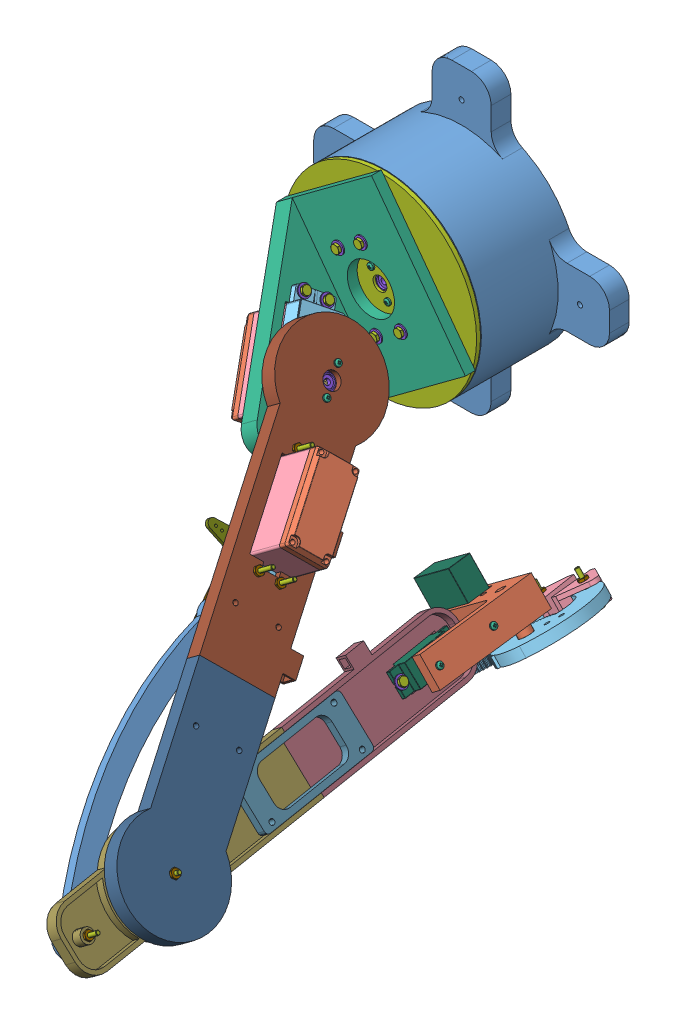
SolidWorks assembly Złożenie1, configuration Domyślna. Lengths in mm.
Overall size (203.19 257.03 301.36).
124 component instances, 27 part files, 135 mates.
Components (placement in the parent):
- Pokrywa-1: Pokrywa [Domyślna] at (39.7266 -62.268 12.8126) size (150 150 49)
- MG_996R-1: MG_996R [Domyślna] at (52.4205 -93.0413 -7.8923) x (-1 0 0) z (0 -1 0) size (19.93 44.4 54.6)
  - Base-1: Base [Domyślna] at (12.6939 -23.8049 -20.4733) size (19.93 6.4 40.73)
  - Eje-1: Eje [Domyślna] at (12.6939 -50.7049 -30.7733) x (-0.837169 0 -0.546944) z (-0.546944 0 0.837169) size (5.78 17.5 5.8)
  - Medio-1: Medio [Domyślna] at (12.6939 -30.2049 -20.4733) size (19.8 20.5 40.6)
  - Top-1: Top [Domyślna] at (12.6939 -59.7049 -20.4733) x (-1 0 0) z (0 0 1) size (19.8 13.2 54.6)
- Złożenie8-1: Złożenie8 [Domyślna] at (-3.3263 -2.2517 0) x (0.998521 0.054362 0) z (0 0 1) size (94.14 109.68 62.96)
  - Mocowanie-1: Mocowanie [Domyślna] at (40.1439 -61.9925 64.2126) x (-0.550863 0.834596 0) z (0 0 1) size (80 60 62.96)
  - MG_996R-1: MG_996R [Domyślna] at (-24.4927 -92.4165 92.8752) x (0.362745 -0.549585 -0.752577) z (-0.414566 0.628098 -0.658505) size (19.93 44.4 54.6)
    - Base-1: Base [Domyślna] at (12.6939 -23.8049 -20.4733) size (19.93 6.4 40.73)
    - Eje-1: Eje [Domyślna] at (12.6939 -50.7049 -30.7733) x (-0.837169 0 -0.546944) z (-0.546944 0 0.837169) size (5.78 17.5 5.8)
    - Medio-1: Medio [Domyślna] at (12.6939 -30.2049 -20.4733) size (19.8 20.5 40.6)
    - Top-1: Top [Domyślna] at (12.6939 -59.7049 -20.4733) x (-1 0 0) z (0 0 1) size (19.8 13.2 54.6)
- Dekiel-3: Dekiel [Domyślna] at (39.7266 -62.268 64.2126) x (-0.595419 0.803416 0) z (0 0 -1) size (98 98 2)
- Orczyk-1: Orczyk [Domyślna] at (39.7266 -62.268 62.2126) x (0.595419 -0.803416 0) z (0.803416 0.595419 0) size (21.5 5.9 21.5)
- Orczyk-2: Orczyk [Domyślna] at (52.3311 -79.4435 103.5865) x (0.375837 -0.507128 0.775608) z (0.461812 -0.623136 -0.631215) size (21.5 5.9 21.5)
- Złożenie3-2: Złożenie3 [Domyślna] at (8.1962 -17.7993 -14.8981) x (0.993577 0.061034 0.095284) z (-0.102991 0.138969 0.984927) size (128.8 189.44 201.48)
  - MG_996R-1: MG_996R [Domyślna] at (112.7095 -80.9773 116.6892) x (-0.360669 0.546439 0.755859) z (-0.416374 0.630837 -0.654735) size (19.93 44.4 54.6)
    - Base-1: Base [Domyślna] at (12.6939 -23.8049 -20.4733) size (19.93 6.4 40.73)
    - Eje-1: Eje [Domyślna] at (12.6939 -50.7049 -30.7733) x (-0.837169 0 -0.546944) z (-0.546944 0 0.837169) size (5.78 17.5 5.8)
    - Medio-1: Medio [Domyślna] at (12.6939 -30.2049 -20.4733) size (19.8 20.5 40.6)
    - Top-1: Top [Domyślna] at (12.6939 -59.7049 -20.4733) x (-1 0 0) z (0 0 1) size (19.8 13.2 54.6)
  - plytka-1: plytka [Domyślna] at (97.1707 -158.5581 182.1546) x (-0.360669 0.546439 0.755859) z (0.834596 0.550863 0) size (28.8 60 5)
  - ramie1-1: ramie1 [Domyślna] at (47.2058 -82.8576 103.5865) x (0.416374 -0.630837 0.654735) z (0.834596 0.550863 0) size (232.1 50 8)
  - ramie-1: ramie [Domyślna] at (47.2058 -82.8576 103.5865) x (0.416374 -0.630837 0.654735) z (0.834596 0.550863 0) size (145 50 8)
- Złożenie4-2: Złożenie4 [Domyślna] at (8.1595 -17.7498 -14.8525) x (0.99359 0.061016 0.095162) z (-0.102859 0.13879 0.984966) size (69.67 92.42 221.23)
  - ramie2-1: ramie2 [Domyślna] at (123.8039 -213.4319 234.5334) x (-0.163325 0.247449 -0.955036) z (0.834596 0.550863 0) size (130 45 13)
  - ramie21-1: ramie21 [Domyślna] at (123.8039 -213.4319 234.5334) x (-0.163325 0.247449 -0.955036) z (0.834596 0.550863 0) size (90 36 6)
  - plytka2-1: plytka2 [Domyślna] at (115.7455 -190.3308 158.1305) x (-0.526093 0.797069 0.29649) z (-0.834596 -0.550863 0) size (25.8 60 4)
  - servo TOWER PRO 9g SG90-1: servo TOWER PRO 9g SG90 [Défaut] at (85.975 -182.4408 103.4882) x (0.163325 -0.247449 0.955036) z (0.834596 0.550863 0) size (32 11.7 29.7)
- 4 Arm-1: 4 Arm [Domyślna] at (57.5904 -115.931 159.4951) x (-0.514712 0.694515 0.502713) z (-0.803416 -0.595419 0) size (39 39 5.5)
- msh-1: msh [По умолчанию] at (119.932 -161.9259 104.7162) x (-0.054685 0.073788 -0.995773) z (-0.803416 -0.595419 0) size (32 7.5 5)
- 111-1: 111 [Domyślna] at (59.2016 -129.4417 159.421) x (-0.299325 0.403888 -0.864453) z (0.803416 0.595419 0) size (54 8 5)
- łacznik-6: łacznik [Domyślna] at (75.4238 -132.4366 180.1679) x (0.318973 -0.430399 0.844401) z (0.502772 -0.678405 -0.535712) size (155 5 25.15)
- podstawa-2: podstawa [Domyślna] at (125.8131 -165.6628 93.5718) x (0.054685 -0.073788 0.995773) z (-0.592902 0.80002 0.091843) size (60 50 19)
- servo TOWER PRO 9g SG90-3: servo TOWER PRO 9g SG90 [Défaut] at (91.2204 -151.7359 70.1421) x (0.803416 0.595419 0) z (0.592902 -0.80002 -0.091843) size (32 11.7 29.7)
- msh1-1: msh1 [По умолчанию] at (98.4601 -188.7964 72.7727) x (-0.566783 -0.333567 -0.753319) z (-0.592902 0.80002 0.091843) size (19.75 7.5 5)
- Złożenie6-3: Złożenie6 [Domyślna] at (10.171 -11.3916 -10.0611) x (0.989879 0.051709 0.132161) z (-0.136721 0.097784 0.985772) size (46 32 64.72)
  - Chwyt-1: Chwyt [Domyślna] at (88.6962 -174.049 17.2042) x (0.795979 0.579475 -0.175003) z (0.533395 -0.808131 -0.249828) size (17.08 20 10)
  - koło_zębate-1: koło_zębate [ISO - Spur gear 1M 30T 20PA 6FW ---S30A75H50L5.0N] at (91.8364 -192.3197 50.9877) x (-0.533395 0.808131 0.249828) z (-0.795979 -0.579475 0.175003) size (5 55.03 34.65)
- Złożenie7-3: Złożenie7 [Domyślna] at (19.6552 -4.3213 -10.4227) x (0.973641 0.028873 0.226252) z (-0.227135 0.032206 0.973331) size (44.29 32.31 61.31)
  - Chwyt-1: Chwyt [Domyślna] at (93.516 -171.6593 20.5651) x (-0.818033 -0.567973 0.090709) z (0.533395 -0.808131 -0.249828) size (17.08 20 10)
  - koło_zębate-1: koło_zębate [ISO - Spur gear 1M 30T 20PA 6FW ---S30A75H50L5.0N] at (114.1006 -171.5915 52.2868) x (0.533395 -0.808131 -0.249828) z (0.818033 0.567973 -0.090709) size (5 55.03 34.65)
- pan head cross recess screw_din-1: pan head cross recess screw_din [DIN EN ISO 7045 - M1.6 x 8 - Z - 8N] at (58.4543 -80.4838 109.0933) x (-0.803416 -0.595419 0) z (0 0 1) size (9.27 3.2 3.2)
- pan head cross recess screw_din-4: pan head cross recess screw_din [DIN EN ISO 7045 - M1.6 x 8 - Z - 8N] at (53.1174 -73.2826 98.0797) x (-0.803416 -0.595419 0) z (0 0 -1) size (9.27 3.2 3.2)
- pan head cross recess screw_din-5: pan head cross recess screw_din [DIN EN ISO 7045 - M1.6 x 8 - Z - 8N] at (35.4992 -56.5637 65.5126) x (0 0 -1) z (1 0 0) size (9.27 3.2 3.2)
- pan head cross recess screw_din-6: pan head cross recess screw_din [DIN EN ISO 7045 - M1.6 x 8 - Z - 8N] at (43.9541 -67.9722 65.5126) x (0 0 -1) z (-1 0 0) size (9.27 3.2 3.2)
- pan head cross recess screw_din-7: pan head cross recess screw_din [DIN EN ISO 7045 - M1.6 x 8 - Z - 8N] at (124.2006 -157.1049 90.2775) x (-0.803416 -0.595419 0) z (0 0 1) size (9.27 3.2 3.2)
- pan head cross recess screw_din-8: pan head cross recess screw_din [DIN EN ISO 7045 - M1.6 x 8 - Z - 8N] at (125.7864 -159.2447 119.1549) x (-0.803416 -0.595419 0) z (0 0 1) size (9.27 3.2 3.2)
- pan head cross recess screw_din-9: pan head cross recess screw_din [DIN EN ISO 7045 - M1.6 x 8 - Z - 8N] at (93.977 -198.6733 61.2709) x (-0.592902 0.80002 0.091843) z (0.742225 0.498675 0.447688) size (9.27 3.2 3.2)
- hex screw gradeab_din-1: hex screw gradeab_din [DIN EN 24017 - M2 x 20-N] at (44.7266 -97.458 47.6126) x (0 0 -1) z (0.923728 0.383049 0) size (21.4 4.62 4)
- plain washer 6902 type abc_din-1: plain washer 6902 type abc_din [DIN 6902-A2.25] at (44.7266 -97.458 45.6126) x (0 0 1) z (0 -1 0) size (0.6 6 6)
- hex thin nut chamfered gradeab_din-2: hex thin nut chamfered gradeab_din [Hexagon Thin Nut ISO 4035 - M2 - N] at (44.7266 -97.458 31.5126) x (0.866025 0.5 0) z (0 0 -1) size (4 4.62 1.2)
- hex thin nut chamfered gradeab_din-3: hex thin nut chamfered gradeab_din [Hexagon Thin Nut ISO 4035 - M2 - N] at (44.7266 -47.958 31.5126) x (0.866025 0.5 0) z (0 0 -1) size (4 4.62 1.2)
- plain washer 6902 type abc_din-3: plain washer 6902 type abc_din [DIN 6902-A2.25] at (44.7266 -47.958 45.6126) x (0 0 1) z (0 -1 0) size (0.6 6 6)
- hex screw gradeab_din-2: hex screw gradeab_din [DIN EN 24017 - M2 x 16-N] at (44.7266 -47.958 47.6126) x (0 0 -1) z (0.923728 0.383049 0) size (17.4 4.62 4)
- hex screw gradeab_din-3: hex screw gradeab_din [DIN EN 24017 - M2 x 20-N] at (34.7266 -97.458 47.6126) x (0 0 -1) z (0.923728 0.383049 0) size (21.4 4.62 4)
- hex screw gradeab_din-4: hex screw gradeab_din [DIN EN 24017 - M2 x 16-N] at (34.7266 -47.958 47.6126) x (0 0 -1) z (0.923728 0.383049 0) size (17.4 4.62 4)
- plain washer 6902 type abc_din-4: plain washer 6902 type abc_din [DIN 6902-A2.25] at (34.7266 -97.458 45.6126) x (0 0 1) z (0 -1 0) size (0.6 6 6)
- plain washer 6902 type abc_din-5: plain washer 6902 type abc_din [DIN 6902-A2.25] at (34.7266 -47.958 45.6126) x (0 0 1) z (0 -1 0) size (0.6 6 6)
- hex thin nut chamfered gradeab_din-4: hex thin nut chamfered gradeab_din [Hexagon Thin Nut ISO 4035 - M2 - N] at (34.7266 -97.458 31.5126) x (0.866025 0.5 0) z (0 0 -1) size (4 4.62 1.2)
- hex thin nut chamfered gradeab_din-5: hex thin nut chamfered gradeab_din [Hexagon Thin Nut ISO 4035 - M2 - N] at (34.7266 -47.958 31.5126) x (0.866025 0.5 0) z (0 0 -1) size (4 4.62 1.2)
- hex screw gradeab_din-5: hex screw gradeab_din [DIN EN 24017 - M2 x 16-N] at (35.3324 -43.7425 71.2126) x (0 0 -1) z (0.923728 0.383049 0) size (17.4 4.62 4)
- plain washer 6902 type abc_din-6: plain washer 6902 type abc_din [DIN 6902-A2.25] at (35.3324 -43.7425 69.2126) x (0 0 1) z (0 -1 0) size (0.6 6 6)
- hex thin nut chamfered gradeab_din-6: hex thin nut chamfered gradeab_din [Hexagon Thin Nut ISO 4035 - M2 - N] at (35.3324 -43.7425 61.0126) x (0.866025 0.5 0) z (0 0 -1) size (4 4.62 1.2)
- hex screw gradeab_din-27: hex screw gradeab_din [DIN EN 24017 - M2 x 16-N] at (55.6262 -72.7419 71.2126) x (0 0 -1) z (0.923728 0.383049 0) size (17.4 4.62 4)
- hex screw gradeab_din-7: hex screw gradeab_din [DIN EN 24017 - M2 x 16-N] at (23.8271 -51.794 71.2126) x (0 0 -1) z (0.923728 0.383049 0) size (17.4 4.62 4)
- hex screw gradeab_din-8: hex screw gradeab_din [DIN EN 24017 - M2 x 16-N] at (43.1073 -81.0049 71.2126) x (0 0 -1) z (0.923728 0.383049 0) size (17.4 4.62 4)
- plain washer 6902 type abc_din-7: plain washer 6902 type abc_din [DIN 6902-A2.25] at (55.6262 -72.7419 69.2126) x (0 0 1) z (0 -1 0) size (0.6 6 6)
- plain washer 6902 type abc_din-8: plain washer 6902 type abc_din [DIN 6902-A2.25] at (23.8271 -51.794 69.2126) x (0 0 1) z (0 -1 0) size (0.6 6 6)
- plain washer 6902 type abc_din-9: plain washer 6902 type abc_din [DIN 6902-A2.25] at (43.1073 -81.0049 69.2126) x (0 0 1) z (0 -1 0) size (0.6 6 6)
- hex thin nut chamfered gradeab_din-7: hex thin nut chamfered gradeab_din [Hexagon Thin Nut ISO 4035 - M2 - N] at (55.6262 -72.7419 61.0126) x (0.866025 0.5 0) z (0 0 -1) size (4 4.62 1.2)
- hex thin nut chamfered gradeab_din-8: hex thin nut chamfered gradeab_din [Hexagon Thin Nut ISO 4035 - M2 - N] at (23.8271 -51.794 61.0126) x (0.866025 0.5 0) z (0 0 -1) size (4 4.62 1.2)
- hex thin nut chamfered gradeab_din-9: hex thin nut chamfered gradeab_din [Hexagon Thin Nut ISO 4035 - M2 - N] at (43.1073 -81.0049 61.0126) x (0.866025 0.5 0) z (0 0 -1) size (4 4.62 1.2)
- hex screw gradeab_din-9: hex screw gradeab_din [DIN EN 24017 - M2 x 16-N] at (26.7931 -69.5049 76.6508) x (-0.803416 -0.595419 0) z (-0.592276 0.799175 0.102607) size (17.4 4.62 4)
- plain washer 6902 type abc_din-10: plain washer 6902 type abc_din [DIN 6902-A2.25] at (25.1863 -70.6957 76.6508) x (0.803416 0.595419 0) z (0.481407 -0.649576 0.588471) size (0.6 6 6)
- hex thin nut chamfered gradeab_din-10: hex thin nut chamfered gradeab_din [Hexagon Thin Nut ISO 4035 - M2 - N] at (13.9385 -79.0316 76.6508) x (-0.327149 0.441431 0.835531) z (-0.803416 -0.595419 0) size (4 4.62 1.2)
- hex screw gradeab_din-10: hex screw gradeab_din [DIN EN 24017 - M2 x 16-N] at (111.5865 -171.155 123.8102) x (-0.803416 -0.595419 0) z (0.140412 -0.189462 -0.971797) size (17.4 4.62 4)
- plain washer 6902 type abc_din-11: plain washer 6902 type abc_din [DIN 6902-A2.25] at (109.9797 -172.3458 123.8102) x (0.803416 0.595419 0) z (0.480708 -0.648634 0.59008) size (0.6 6 6)
- hex thin nut chamfered gradeab_din-11: hex thin nut chamfered gradeab_din [Hexagon Thin Nut ISO 4035 - M2 - N] at (105.8019 -175.442 123.8102) x (0.063919 -0.086248 -0.994221) z (-0.803416 -0.595419 0) size (4 4.62 1.2)
- hex screw gradeab_din-11: hex screw gradeab_din [DIN EN 24017 - M2 x 20-N] at (115.4473 -189.8003 258.7081) x (0.803416 0.595419 0) z (0.083424 -0.112566 -0.990136) size (21.4 4.62 4)
- plain washer 6902 type abc_din-12: plain washer 6902 type abc_din [DIN 6902-A2.25] at (117.0541 -188.6095 258.7081) x (-0.803416 -0.595419 0) z (-0.576535 0.777935 0.249848) size (0.6 6 6)
- hex thin nut chamfered gradeab_din-12: hex thin nut chamfered gradeab_din [Hexagon Thin Nut ISO 4035 - M2 - N] at (130.8729 -178.3683 258.7081) x (0.159434 -0.215129 -0.963483) z (0.803416 0.595419 0) size (4 4.62 1.2)
- hex screw gradeab_din-12: hex screw gradeab_din [DIN EN 24017 - M2 x 16-N] at (57.5347 -94.5265 130.2047) x (0.803416 0.595419 0) z (-0.295441 0.398648 0.868213) size (17.4 4.62 4)
- plain washer 6902 type abc_din-13: plain washer 6902 type abc_din [DIN 6902-A2.25] at (59.1416 -93.3356 130.2047) x (-0.803416 -0.595419 0) z (0.59069 -0.797035 0.125777) size (0.6 6 6)
- hex thin nut chamfered gradeab_din-13: hex thin nut chamfered gradeab_din [Hexagon Thin Nut ISO 4035 - M2 - N] at (64.7655 -89.1677 130.2047) x (-0.360202 0.486031 0.796259) z (0.803416 0.595419 0) size (4 4.62 1.2)
- hex screw gradeab_din-13: hex screw gradeab_din [DIN EN 24017 - M2 x 16-N] at (117.0672 -194.9253 298.384) x (0.803416 0.595419 0) z (-0.02438 0.032896 0.999161) size (17.4 4.62 4)
- plain washer 6902 type abc_din-14: plain washer 6902 type abc_din [DIN 6902-A2.25] at (118.4732 -193.8833 298.384) x (-0.803416 -0.595419 0) z (0.576535 -0.777935 -0.249848) size (0.6 6 6)
- hex thin nut chamfered gradeab_din-14: hex thin nut chamfered gradeab_din [Hexagon Thin Nut ISO 4035 - M2 - N] at (126.668 -187.81 298.384) x (0.159434 -0.215129 -0.963483) z (0.803416 0.595419 0) size (4 4.62 1.2)
- hex screw gradeab_din-14: hex screw gradeab_din [DIN EN 24017 - M2 x 16-N] at (109.4684 -168.2969 96.0371) x (-0.803416 -0.595419 0) z (0.140412 -0.189462 -0.971797) size (17.4 4.62 4)
- plain washer 6902 type abc_din-15: plain washer 6902 type abc_din [DIN 6902-A2.25] at (107.8616 -169.4877 96.0371) x (0.803416 0.595419 0) z (0.480708 -0.648634 0.59008) size (0.6 6 6)
- hex thin nut chamfered gradeab_din-15: hex thin nut chamfered gradeab_din [Hexagon Thin Nut ISO 4035 - M2 - N] at (103.6838 -172.5839 96.0371) x (0.063919 -0.086248 -0.994221) z (-0.803416 -0.595419 0) size (4 4.62 1.2)
- hex screw gradeab_din-15: hex screw gradeab_din [DIN EN 24017 - M2 x 20-N] at (126.5943 -176.374 72.1481) x (-0.592902 0.80002 0.091843) z (0.57607 0.341684 0.74256) size (21.4 4.62 4)
- plain washer 6902 type abc_din-16: plain washer 6902 type abc_din [DIN 6902-A2.25] at (125.4085 -174.7739 72.3318) x (0.592902 -0.80002 -0.091843) z (0.299102 0.324677 -0.897287) size (0.6 6 6)
- hex thin nut chamfered gradeab_din-16: hex thin nut chamfered gradeab_din [Hexagon Thin Nut ISO 4035 - M2 - N] at (116.3964 -162.6136 73.7278) x (0.497947 0.2746 0.822583) z (-0.592902 0.80002 0.091843) size (4 4.62 1.2)
- hex screw gradeab_din-16: hex screw gradeab_din [DIN EN 24017 - M2 x 16-N] at (123.9705 -176.7645 36.8358) x (-0.592902 0.80002 0.091843) z (0.577534 0.342968 0.740829) size (17.4 4.62 4)
- plain washer 6902 type abc_din-17: plain washer 6902 type abc_din [DIN 6902-A2.25] at (122.7847 -175.1645 37.0195) x (0.592902 -0.80002 -0.091843) z (0.297153 0.323361 -0.898408) size (0.6 6 6)
- hex thin nut chamfered gradeab_din-17: hex thin nut chamfered gradeab_din [Hexagon Thin Nut ISO 4035 - M2 - N] at (116.1442 -166.2043 38.0481) x (0.497947 0.2746 0.822583) z (-0.592902 0.80002 0.091843) size (4 4.62 1.2)
- hex screw gradeab_din-17: hex screw gradeab_din [DIN EN 24017 - M2 x 16-N] at (102.2465 -193.1038 36.7434) x (-0.592902 0.80002 0.091843) z (0.770886 0.530906 0.351957) size (17.4 4.62 4)
- plain washer 6902 type abc_din-18: plain washer 6902 type abc_din [DIN 6902-A2.25] at (101.0607 -191.5038 36.9271) x (0.592902 -0.80002 -0.091843) z (0.299102 0.324677 -0.897287) size (0.6 6 6)
- hex thin nut chamfered gradeab_din-18: hex thin nut chamfered gradeab_din [Hexagon Thin Nut ISO 4035 - M2 - N] at (94.4202 -182.5436 37.9557) x (0.497947 0.2746 0.822583) z (-0.592902 0.80002 0.091843) size (4 4.62 1.2)
- hex thin nut chamfered gradeab_din-19: hex thin nut chamfered gradeab_din [Hexagon Thin Nut ISO 4035 - M2 - N] at (33.7024 -108.8716 109.4312) x (-0.302668 0.458563 0.835531) z (-0.834596 -0.550863 0) size (4 4.62 1.2)
- hex thin nut chamfered gradeab_din-20: hex thin nut chamfered gradeab_din [Hexagon Thin Nut ISO 4035 - M2 - N] at (9.5539 -72.2849 84.361) x (-0.302668 0.458563 0.835531) z (-0.834596 -0.550863 0) size (4 4.62 1.2)
- hex thin nut chamfered gradeab_din-21: hex thin nut chamfered gradeab_din [Hexagon Thin Nut ISO 4035 - M2 - N] at (30.0749 -103.3757 116.957) x (-0.302668 0.458563 0.835531) z (-0.834596 -0.550863 0) size (4 4.62 1.2)
- plain washer 6902 type abc_din-19: plain washer 6902 type abc_din [DIN 6902-A2.25] at (45.3867 -101.1595 109.4312) x (0.834596 0.550863 0) z (0.445383 -0.674786 0.588471) size (0.6 6 6)
- plain washer 6902 type abc_din-20: plain washer 6902 type abc_din [DIN 6902-A2.25] at (21.2383 -64.5728 84.361) x (0.834596 0.550863 0) z (0.445383 -0.674786 0.588471) size (0.6 6 6)
- plain washer 6902 type abc_din-21: plain washer 6902 type abc_din [DIN 6902-A2.25] at (41.7593 -95.6637 116.957) x (0.834596 0.550863 0) z (0.445383 -0.674786 0.588471) size (0.6 6 6)
- hex screw gradeab_din-25: hex screw gradeab_din [DIN EN 24017 - M2 x 16-N] at (47.0559 -100.0578 109.4312) x (-0.834596 -0.550863 0) z (-0.547955 0.830191 0.102607) size (17.4 4.62 4)
- hex screw gradeab_din-19: hex screw gradeab_din [DIN EN 24017 - M2 x 16-N] at (22.9074 -63.4711 84.361) x (-0.834596 -0.550863 0) z (-0.547955 0.830191 0.102607) size (17.4 4.62 4)
- hex screw gradeab_din-20: hex screw gradeab_din [DIN EN 24017 - M2 x 16-N] at (43.4285 -94.5619 116.957) x (-0.834596 -0.550863 0) z (-0.547955 0.830191 0.102607) size (17.4 4.62 4)
- hex thin nut chamfered gradeab_din-22: hex thin nut chamfered gradeab_din [Hexagon Thin Nut ISO 4035 - M2 - N] at (83.3694 -114.2705 168.5973) x (-0.360202 0.486031 0.796259) z (0.803416 0.595419 0) size (4 4.62 1.2)
- hex thin nut chamfered gradeab_din-23: hex thin nut chamfered gradeab_din [Hexagon Thin Nut ISO 4035 - M2 - N] at (69.3836 -95.399 123.8926) x (-0.360202 0.486031 0.796259) z (0.803416 0.595419 0) size (4 4.62 1.2)
- hex thin nut chamfered gradeab_din-24: hex thin nut chamfered gradeab_din [Hexagon Thin Nut ISO 4035 - M2 - N] at (87.9875 -120.5019 162.2852) x (-0.360202 0.486031 0.796259) z (0.803416 0.595419 0) size (4 4.62 1.2)
- plain washer 6902 type abc_din-22: plain washer 6902 type abc_din [DIN 6902-A2.25] at (77.7455 -118.4384 168.5973) x (-0.803416 -0.595419 0) z (0.59069 -0.797035 0.125777) size (0.6 6 6)
- plain washer 6902 type abc_din-23: plain washer 6902 type abc_din [DIN 6902-A2.25] at (63.7597 -99.567 123.8926) x (-0.803416 -0.595419 0) z (0.59069 -0.797035 0.125777) size (0.6 6 6)
- plain washer 6902 type abc_din-24: plain washer 6902 type abc_din [DIN 6902-A2.25] at (82.3636 -124.6698 162.2852) x (-0.803416 -0.595419 0) z (0.59069 -0.797035 0.125777) size (0.6 6 6)
- hex screw gradeab_din-26: hex screw gradeab_din [DIN EN 24017 - M2 x 16-N] at (76.1387 -119.6293 168.5973) x (0.803416 0.595419 0) z (-0.295441 0.398648 0.868213) size (17.4 4.62 4)
- hex screw gradeab_din-22: hex screw gradeab_din [DIN EN 24017 - M2 x 16-N] at (62.1529 -100.7578 123.8926) x (0.803416 0.595419 0) z (-0.295441 0.398648 0.868213) size (17.4 4.62 4)
- hex screw gradeab_din-23: hex screw gradeab_din [DIN EN 24017 - M2 x 16-N] at (80.7568 -125.8606 162.2852) x (0.803416 0.595419 0) z (-0.295441 0.398648 0.868213) size (17.4 4.62 4)
- hex screw gradeab_din-24: hex screw gradeab_din [DIN EN 24017 - M2 x 16-N] at (64.7786 -140.3258 180.1679) x (0.803416 0.595419 0) z (0.083424 -0.112566 -0.990136) size (17.4 4.62 4)
- plain washer 6902 type abc_din-25: plain washer 6902 type abc_din [DIN 6902-A2.25] at (66.3854 -139.135 180.1679) x (-0.803416 -0.595419 0) z (-0.573916 0.774402 0.266312) size (0.6 6 6)
- hex thin nut chamfered gradeab_din-25: hex thin nut chamfered gradeab_din [Hexagon Thin Nut ISO 4035 - M2 - N] at (76.3879 -131.7221 180.1679) x (0.159434 -0.215129 -0.963483) z (0.803416 0.595419 0) size (4 4.62 1.2)
- pan head cross recess screw_din-11: pan head cross recess screw_din [DIN EN ISO 7045 - M1.6 x 8 - Z - 8N] at (61.1504 -134.2546 168.0655) x (0.803416 0.595419 0) z (0.220098 -0.296984 -0.92917) size (9.27 3.2 3.2)
- pan head cross recess screw_din-12: pan head cross recess screw_din [DIN EN ISO 7045 - M1.6 x 8 - Z - 8N] at (51.6469 -121.4312 140.6191) x (0.803416 0.595419 0) z (0.220098 -0.296984 -0.92917) size (9.27 3.2 3.2)
Mates (geometry in assembly coordinates):
- Wspólnie31: coincident: plane of MG_996R-1/Eje-1 through (39.7266 -62.268 60.3126) normal (0 0 1); plane of Orczyk-1 through (41.3314 -64.4333 60.3126) normal (0 0 -1)
- Koncentryczne51: concentric: cylinder of MG_996R-1/Eje-1 through (39.7266 -62.268 42.8126) axis (0 0 -1) radius 2.65; cylinder of Orczyk-1 through (39.7266 -62.268 60.3126) axis (0 0 -1) radius 1.4
- Wspólnie32: coincident: line of assembly; line of assembly; axis of Pokrywa-1 through (39.7266 -62.268 42.8126) axis (0 0 -1); axis of Orczyk-1 through (39.7266 -62.268 62.2126) axis (0 0 -1)
- Wspólnie33: coincident: plane of Pokrywa-1 through (39.7266 -62.268 42.8126) normal (0 0 1); plane of MG_996R-1/Top-1 through (39.7266 -72.568 42.8126) normal (0 0 -1)
- Równolegle7: parallel: plane of Pokrywa-1 through (29.2266 -93.268 12.8126) normal (1 0 0); plane of MG_996R-1/Top-1 through (29.8266 -92.868 51.8126) normal (-1 0 0)
- Koncentryczne98: concentric: cylinder of 4 Arm-1 through (58.1144 -116.6381 140.6191) axis (-0.803416 -0.595419 0) radius 0.625; cylinder of 111-1 through (56.7084 -117.6801 140.6191) axis (0.803416 0.595419 0) radius 1.3
- Koncentryczne101: concentric: cylinder of 4 Arm-1 through (67.6179 -129.4615 168.0655) axis (-0.803416 -0.595419 0) radius 0.625; cylinder of 111-1 through (66.2119 -130.5035 168.0655) axis (0.803416 0.595419 0) radius 1.3
- Wspólnie75: coincident: plane of 4 Arm-1 through (56.1844 -116.973 159.4951) normal (-0.803416 -0.595419 0); plane of 111-1 through (69.6724 -135.1728 182.0377) normal (0.803416 0.595419 0)
- Koncentryczne104: concentric: cylinder of msh-1 through (117.5322 -162.0468 90.2775) axis (0.803416 0.595419 0) radius 0.5; cylinder of podstawa-2 through (123.1561 -157.8789 90.2775) axis (0.803416 0.595419 0) radius 1.3
- Koncentryczne105: concentric: cylinder of msh-1 through (119.1181 -164.1867 119.1549) axis (0.803416 0.595419 0) radius 0.5; cylinder of podstawa-2 through (124.742 -160.0188 119.1549) axis (0.803416 0.595419 0) radius 1.3
- Wspólnie77: coincident: plane of msh-1 through (119.932 -161.9259 104.7162) normal (0.803416 0.595419 0); plane of podstawa-2 through (114.2548 -154.2656 83.0001) normal (-0.803416 -0.595419 0)
- Koncentryczne106: concentric: cylinder of servo TOWER PRO 9g SG90-3 through (71.4494 -167.0457 75.8678) axis (0.592902 -0.80002 -0.091843) radius 1.25; cylinder of podstawa-2 through (81.2323 -180.246 74.3524) axis (0.592902 -0.80002 -0.091843) radius 1.3
- Koncentryczne107: concentric: cylinder of servo TOWER PRO 9g SG90-3 through (93.9451 -150.3739 75.8678) axis (0.592902 -0.80002 -0.091843) radius 1.25; cylinder of podstawa-2 through (103.728 -163.5743 74.3524) axis (0.592902 -0.80002 -0.091843) radius 1.3
- Wspólnie78: coincident: plane of podstawa-2 through (118.1054 -155.2625 94.7657) normal (0.592902 -0.80002 -0.091843); plane of servo TOWER PRO 9g SG90-3 through (101.0033 -164.9362 68.6267) normal (-0.592902 0.80002 0.091843)
- Koncentryczne108: concentric: cylinder of servo TOWER PRO 9g SG90-3 through (96.0885 -185.5963 73.14) axis (-0.592902 0.80002 0.091843) radius 2.5; cylinder of msh1-1 through (98.4601 -188.7964 72.7727) axis (-0.592902 0.80002 0.091843) radius 2.5
- Odległość2: distance = 2 mm: plane of msh1-1 through (97.2743 -187.1964 72.9564) normal (-0.592902 0.80002 0.091843); plane of servo TOWER PRO 9g SG90-3 through (96.0885 -185.5963 73.14) normal (0.592902 -0.80002 -0.091843)
- Koncentryczne113: concentric: cylinder of Orczyk-2 through (54.9996 -83.0441 109.0933) axis (0.803416 0.595419 0) radius 0.5; cylinder of pan head cross recess screw_din-1 through (78.861 -65.3602 109.0933) axis (0.803416 0.595419 0) radius 0.8
- Koncentryczne120: concentric: cylinder of podstawa-2 through (123.1561 -157.8789 90.2775) axis (0.803416 0.595419 0) radius 1.3; cylinder of pan head cross recess screw_din-7 through (144.6073 -141.9812 90.2775) axis (0.803416 0.595419 0) radius 0.8
- Wspólnie91: coincident: plane of podstawa-2 through (117.2875 -149.9603 65.0762) normal (0.803416 0.595419 0); plane of pan head cross recess screw_din-7 through (123.6325 -158.5217 90.2775) normal (-0.803416 -0.595419 0)
- Koncentryczne134: concentric: line of assembly; cylinder of assembly; axis of MG_996R-1/Top-1 through (44.7266 -97.458 45.6126) axis (0 0 -1); cylinder of plain washer 6902 type abc_din-1 through (44.7266 -97.458 46.2126) axis (0 0 -1) radius 3
- Wspólnie96: coincident: plane of MG_996R-1/Top-1 through (39.7266 -96.368 45.6126) normal (0 0 1); plane of plain washer 6902 type abc_din-1 through (44.7266 -97.458 45.6126) normal (0 0 -1)
- Koncentryczne135: concentric: cylinder of hex screw gradeab_din-1 through (44.7266 -97.458 47.6126) axis (0 0 1) radius 1; cylinder of plain washer 6902 type abc_din-1 through (44.7266 -97.458 46.2126) axis (0 0 -1) radius 1.125
- Wspólnie97: coincident: plane of hex screw gradeab_din-1 through (43.842 -95.3247 46.2126) normal (0 0 -1); plane of plain washer 6902 type abc_din-1 through (44.7266 -97.458 46.2126) normal (0 0 1)
- Koncentryczne137: concentric: cylinder of hex screw gradeab_din-1 through (44.7266 -97.458 47.6126) axis (0 0 1) radius 1; cylinder of hex thin nut chamfered gradeab_din-2 through (44.7266 -97.458 32.7126) axis (0 0 -1) radius 0.8
- Odległość3: distance = 6.5 mm: plane of hex thin nut chamfered gradeab_din-2 through (45.8813 -99.458 32.7126) normal (0 0 1); plane of hex screw gradeab_din-1 through (44.7266 -97.458 26.2126) normal (0 0 -1)
- Równolegle19: parallel: plane of Pokrywa-1 through (45.8813 -99.268 32.8126) normal (0 1 0); plane of hex thin nut chamfered gradeab_din-2 through (45.8813 -99.458 32.7126) normal (0 -1 0)
- Wspólnie101: coincident: plane of hex screw gradeab_din-5 through (34.4478 -41.6093 69.8126) normal (0 0 -1); plane of plain washer 6902 type abc_din-6 through (35.3324 -43.7425 69.8126) normal (0 0 1)
- Koncentryczne138: concentric: cylinder of hex screw gradeab_din-5 through (35.3324 -43.7425 71.2126) axis (0 0 1) radius 1; cylinder of plain washer 6902 type abc_din-6 through (35.3324 -43.7425 69.8126) axis (0 0 -1) radius 1.125
- Koncentryczne139: concentric: cylinder of hex screw gradeab_din-5 through (35.3324 -43.7425 71.2126) axis (0 0 1) radius 1; cylinder of hex thin nut chamfered gradeab_din-6 through (35.3324 -43.7425 62.2126) axis (0 0 -1) radius 0.8
- Wspólnie104: coincident: plane of hex screw gradeab_din-9 through (25.8094 -70.5289 78.948) normal (-0.803416 -0.595419 0); plane of plain washer 6902 type abc_din-10 through (25.6683 -70.3385 76.6508) normal (0.803416 0.595419 0)
- Koncentryczne141: concentric: cylinder of hex screw gradeab_din-9 through (26.7931 -69.5049 76.6508) axis (0.803416 0.595419 0) radius 1; cylinder of plain washer 6902 type abc_din-10 through (25.6683 -70.3385 76.6508) axis (-0.803416 -0.595419 0) radius 1.125
- Koncentryczne142: concentric: cylinder of hex screw gradeab_din-9 through (26.7931 -69.5049 76.6508) axis (0.803416 0.595419 0) radius 1; cylinder of hex thin nut chamfered gradeab_din-10 through (14.9026 -78.3171 76.6508) axis (-0.803416 -0.595419 0) radius 0.8
- Wspólnie105: coincident: plane of hex screw gradeab_din-10 through (109.1255 -170.1855 123.2656) normal (-0.803416 -0.595419 0); plane of plain washer 6902 type abc_din-11 through (110.4617 -171.9886 123.8102) normal (0.803416 0.595419 0)
- Koncentryczne143: concentric: cylinder of hex screw gradeab_din-10 through (111.5865 -171.155 123.8102) axis (0.803416 0.595419 0) radius 1; cylinder of plain washer 6902 type abc_din-11 through (110.4617 -171.9886 123.8102) axis (-0.803416 -0.595419 0) radius 1.125
- Koncentryczne144: concentric: cylinder of hex screw gradeab_din-10 through (111.5865 -171.155 123.8102) axis (0.803416 0.595419 0) radius 1; cylinder of hex thin nut chamfered gradeab_din-11 through (106.766 -174.7275 123.8102) axis (-0.803416 -0.595419 0) radius 0.8
- Wspólnie106: coincident: plane of hex screw gradeab_din-11 through (117.9336 -190.8039 259.0317) normal (0.803416 0.595419 0); plane of plain washer 6902 type abc_din-12 through (116.5721 -188.9668 258.7081) normal (-0.803416 -0.595419 0)
- Koncentryczne145: concentric: cylinder of hex screw gradeab_din-11 through (115.4473 -189.8003 258.7081) axis (-0.803416 -0.595419 0) radius 1; cylinder of plain washer 6902 type abc_din-12 through (116.5721 -188.9668 258.7081) axis (0.803416 0.595419 0) radius 1.125
- Koncentryczne146: concentric: cylinder of hex screw gradeab_din-11 through (115.4473 -189.8003 258.7081) axis (-0.803416 -0.595419 0) radius 1; cylinder of hex thin nut chamfered gradeab_din-12 through (129.9088 -179.0828 258.7081) axis (0.803416 0.595419 0) radius 0.8
- Wspólnie107: coincident: plane of hex screw gradeab_din-12 through (57.4657 -92.082 129.0588) normal (0.803416 0.595419 0); plane of plain washer 6902 type abc_din-13 through (58.6595 -93.6929 130.2047) normal (-0.803416 -0.595419 0)
- Koncentryczne147: concentric: cylinder of hex screw gradeab_din-12 through (57.5347 -94.5265 130.2047) axis (-0.803416 -0.595419 0) radius 1; cylinder of plain washer 6902 type abc_din-13 through (58.6595 -93.6929 130.2047) axis (0.803416 0.595419 0) radius 1.125
- Koncentryczne148: concentric: cylinder of hex screw gradeab_din-12 through (57.5347 -94.5265 130.2047) axis (-0.803416 -0.595419 0) radius 1; cylinder of hex thin nut chamfered gradeab_din-13 through (63.8014 -89.8822 130.2047) axis (0.803416 0.595419 0) radius 0.8
- Wspólnie109: coincident: plane of hex screw gradeab_din-14 through (107.0073 -167.3274 95.4925) normal (-0.803416 -0.595419 0); plane of plain washer 6902 type abc_din-15 through (108.3436 -169.1305 96.0371) normal (0.803416 0.595419 0)
- Koncentryczne151: concentric: cylinder of hex screw gradeab_din-14 through (109.4684 -168.2969 96.0371) axis (0.803416 0.595419 0) radius 1; cylinder of plain washer 6902 type abc_din-15 through (108.3436 -169.1305 96.0371) axis (-0.803416 -0.595419 0) radius 1.125
- Koncentryczne152: concentric: cylinder of hex screw gradeab_din-14 through (109.4684 -168.2969 96.0371) axis (0.803416 0.595419 0) radius 1; cylinder of hex thin nut chamfered gradeab_din-15 through (104.6479 -171.8694 96.0371) axis (-0.803416 -0.595419 0) radius 0.8
- Wspólnie110: coincident: plane of hex screw gradeab_din-15 through (124.4648 -176.3929 73.8089) normal (-0.592902 0.80002 0.091843); plane of plain washer 6902 type abc_din-16 through (125.7643 -175.254 72.2767) normal (0.592902 -0.80002 -0.091843)
- Koncentryczne153: concentric: cylinder of hex screw gradeab_din-15 through (126.5943 -176.374 72.1481) axis (0.592902 -0.80002 -0.091843) radius 1; cylinder of plain washer 6902 type abc_din-16 through (125.7643 -175.254 72.2767) axis (-0.592902 0.80002 0.091843) radius 1.125
- Koncentryczne154: concentric: cylinder of hex screw gradeab_din-15 through (126.5943 -176.374 72.1481) axis (0.592902 -0.80002 -0.091843) radius 1; cylinder of hex thin nut chamfered gradeab_din-16 through (117.1079 -163.5737 73.6176) axis (-0.592902 0.80002 0.091843) radius 0.8
- Wspólnie144: coincident: circle of podstawa-2; plane of hex thin nut chamfered gradeab_din-16 through (118.5694 -162.3417 72.3216) normal (0.592902 -0.80002 -0.091843)
- Wspólnie111: coincident: plane of hex screw gradeab_din-16 through (121.8445 -176.7814 38.501) normal (-0.592902 0.80002 0.091843); plane of plain washer 6902 type abc_din-17 through (123.1405 -175.6445 36.9643) normal (0.592902 -0.80002 -0.091843)
- Koncentryczne155: concentric: cylinder of hex screw gradeab_din-16 through (123.9705 -176.7645 36.8358) axis (0.592902 -0.80002 -0.091843) radius 1; cylinder of plain washer 6902 type abc_din-17 through (123.1405 -175.6445 36.9643) axis (-0.592902 0.80002 0.091843) radius 1.125
- Koncentryczne156: concentric: cylinder of hex screw gradeab_din-16 through (123.9705 -176.7645 36.8358) axis (0.592902 -0.80002 -0.091843) radius 1; cylinder of hex thin nut chamfered gradeab_din-17 through (116.8557 -167.1643 37.9379) axis (-0.592902 0.80002 0.091843) radius 0.8
- Wspólnie112: coincident: plane of hex screw gradeab_din-17 through (100.8788 -192.6292 39.0232) normal (-0.592902 0.80002 0.091843); plane of plain washer 6902 type abc_din-18 through (101.4164 -191.9838 36.872) normal (0.592902 -0.80002 -0.091843)
- Koncentryczne157: concentric: cylinder of hex screw gradeab_din-17 through (102.2465 -193.1038 36.7434) axis (0.592902 -0.80002 -0.091843) radius 1; cylinder of plain washer 6902 type abc_din-18 through (101.4164 -191.9838 36.872) axis (-0.592902 0.80002 0.091843) radius 1.125
- Koncentryczne158: concentric: cylinder of hex screw gradeab_din-17 through (102.2465 -193.1038 36.7434) axis (0.592902 -0.80002 -0.091843) radius 1; cylinder of hex thin nut chamfered gradeab_din-18 through (95.1317 -183.5036 37.8455) axis (-0.592902 0.80002 0.091843) radius 0.8
- Wspólnie122: coincident: plane of łacznik-6 through (154.4063 -242.3689 218.6471) normal (-0.803416 -0.595419 0); plane of plain washer 6902 type abc_din-14 through (118.4732 -193.8833 298.384) normal (0.803416 0.595419 0)
- Wspólnie123: coincident: plane of hex screw gradeab_din-24 through (67.2649 -141.3294 180.4914) normal (0.803416 0.595419 0); plane of plain washer 6902 type abc_din-25 through (65.9034 -139.4923 180.1679) normal (-0.803416 -0.595419 0)
- Koncentryczne168: concentric: cylinder of hex screw gradeab_din-24 through (64.7786 -140.3258 180.1679) axis (-0.803416 -0.595419 0) radius 1; cylinder of plain washer 6902 type abc_din-25 through (65.9034 -139.4923 180.1679) axis (0.803416 0.595419 0) radius 1.125
- Koncentryczne169: concentric: cylinder of hex screw gradeab_din-24 through (64.7786 -140.3258 180.1679) axis (-0.803416 -0.595419 0) radius 1; cylinder of hex thin nut chamfered gradeab_din-25 through (75.4238 -132.4366 180.1679) axis (0.803416 0.595419 0) radius 0.8
- Wspólnie127: coincident: plane of łacznik-6 through (156.0131 -241.178 218.6471) normal (0.803416 0.595419 0); plane of hex thin nut chamfered gradeab_din-25 through (74.099 -130.6489 179.5495) normal (-0.803416 -0.595419 0)
- Koncentryczne170: concentric: cylinder of 111-1 through (70.4025 -136.1579 180.1679) axis (0.803416 0.595419 0) radius 1.3; cylinder of hex screw gradeab_din-24 through (64.7786 -140.3258 180.1679) axis (-0.803416 -0.595419 0) radius 1
- Wspólnie124: coincident: plane of 111-1 through (65.6553 -138.1499 182.0377) normal (-0.803416 -0.595419 0); plane of plain washer 6902 type abc_din-25 through (66.3854 -139.135 180.1679) normal (0.803416 0.595419 0)
- Koncentryczne171: concentric: cylinder of 111-1 through (66.2119 -130.5035 168.0655) axis (0.803416 0.595419 0) radius 1.3; cylinder of pan head cross recess screw_din-11 through (40.7437 -149.3783 168.0655) axis (-0.803416 -0.595419 0) radius 0.8
- Wspólnie125: coincident: plane of 111-1 through (65.6553 -138.1499 182.0377) normal (-0.803416 -0.595419 0); plane of pan head cross recess screw_din-11 through (62.6375 -134.0778 168.3612) normal (0.803416 0.595419 0)
- Koncentryczne172: concentric: cylinder of 111-1 through (56.7084 -117.6801 140.6191) axis (0.803416 0.595419 0) radius 1.3; cylinder of pan head cross recess screw_din-12 through (31.2401 -136.5548 140.6191) axis (-0.803416 -0.595419 0) radius 0.8
- Wspólnie126: coincident: plane of 111-1 through (65.6553 -138.1499 182.0377) normal (-0.803416 -0.595419 0); plane of pan head cross recess screw_din-12 through (53.1339 -121.2544 140.9148) normal (0.803416 0.595419 0)
- Koncentryczne173: concentric: cylinder of hex thin nut chamfered gradeab_din-19 through (34.7039 -108.2106 109.4312) axis (-0.834596 -0.550863 0) radius 0.8; cylinder of hex screw gradeab_din-25 through (47.0559 -100.0578 109.4312) axis (0.834596 0.550863 0) radius 1
- Koncentryczne174: concentric: cylinder of hex thin nut chamfered gradeab_din-20 through (10.5554 -71.6239 84.361) axis (-0.834596 -0.550863 0) radius 0.8; cylinder of hex screw gradeab_din-19 through (22.9074 -63.4711 84.361) axis (0.834596 0.550863 0) radius 1
- Wspólnie140: coincident: line of assembly; line of assembly; axis of 111-1 through (66.3854 -139.135 180.1679) axis (0.803416 0.595419 0); axis of łacznik-6 through (71.4068 -135.4136 180.1679) axis (0.803416 0.595419 0)
- Wspólnie141: coincident: plane of łacznik-6 through (154.4063 -242.3689 218.6471) normal (-0.803416 -0.595419 0); plane of plain washer 6902 type abc_din-14 through (118.4732 -193.8833 298.384) normal (0.803416 0.595419 0)
- Koncentryczne176: concentric: circle of łacznik-6; cylinder of plain washer 6902 type abc_din-14 through (117.9912 -194.2405 298.384) axis (0.803416 0.595419 0) radius 1.125
- Koncentryczne177: concentric: cylinder of łacznik-6 through (118.4732 -193.8833 298.384) axis (-0.803416 -0.595419 0) radius 1.3; cylinder of hex screw gradeab_din-13 through (117.0672 -194.9253 298.384) axis (-0.803416 -0.595419 0) radius 1
- Wspólnie143: coincident: plane of plain washer 6902 type abc_din-14 through (117.9912 -194.2405 298.384) normal (-0.803416 -0.595419 0); plane of hex screw gradeab_din-13 through (116.8013 -192.6351 298.3021) normal (0.803416 0.595419 0)
- Koncentryczne178: concentric: cylinder of hex screw gradeab_din-13 through (117.0672 -194.9253 298.384) axis (-0.803416 -0.595419 0) radius 1; cylinder of hex thin nut chamfered gradeab_din-14 through (125.7039 -188.5245 298.384) axis (0.803416 0.595419 0) radius 0.8
- Koncentryczne181: concentric: cylinder of msh1-1 through (89.056 -192.0331 62.0332) axis (0.592902 -0.80002 -0.091843) radius 0.5; cylinder of pan head cross recess screw_din-9 through (109.0368 -218.9938 58.9381) axis (0.592902 -0.80002 -0.091843) radius 0.8
- Koncentryczne232: concentric: cylinder of assembly; cylinder of assembly; axis of ?; cylinder of Orczyk-1 through (43.9541 -67.9722 62.2126) axis (0 0 1) radius 0.5; cylinder of Dekiel-3 through (43.9541 -67.9722 64.2126) axis (0 0 1) radius 1.3
- Koncentryczne233: concentric: cylinder of Dekiel-3 through (35.4992 -56.5637 64.2126) axis (0 0 1) radius 1.3; circle of Orczyk-1
- Wspólnie212: coincident: plane of Dekiel-3 through (39.7266 -62.268 62.2126) normal (0 0 -1); plane of Orczyk-1 through (39.7266 -62.268 62.2126) normal (0 0 1)
- Koncentryczne234: concentric: cylinder of Dekiel-3 through (35.4992 -56.5637 64.2126) axis (0 0 1) radius 1.3; cylinder of pan head cross recess screw_din-5 through (35.4992 -56.5637 90.9126) axis (0 0 1) radius 1.6
- Wspólnie213: coincident: plane of Dekiel-3 through (39.7266 -62.268 64.2126) normal (0 0 1); circle of pan head cross recess screw_din-5
- Wspólnie214: coincident: plane of Dekiel-3 through (39.7266 -62.268 62.2126) normal (0 0 -1); plane of hex thin nut chamfered gradeab_din-6 through (36.4871 -45.7425 62.2126) normal (0 0 1)
- Wspólnie217: coincident: plane of Złożenie4^Złożenie1-1/Chwyt-1 through (91.1171 -186.5532 38.4936) normal (-0.592902 0.80002 0.091843); plane of hex thin nut chamfered gradeab_din-18 through (96.5932 -182.2716 36.5495) normal (0.592902 -0.80002 -0.091843)
- Koncentryczne236: concentric: cylinder of Złożenie4^Złożenie1-1/Chwyt-1 through (101.0607 -191.5038 36.9271) axis (0.592902 -0.80002 -0.091843) radius 1.3; cylinder of hex screw gradeab_din-17 through (102.2465 -193.1038 36.7434) axis (0.592902 -0.80002 -0.091843) radius 1
- Wspólnie218: coincident: plane of Złożenie4^Złożenie1-1/Chwyt-1 through (97.0461 -194.5534 37.5752) normal (0.592902 -0.80002 -0.091843); plane of plain washer 6902 type abc_din-18 through (101.0607 -191.5038 36.9271) normal (-0.592902 0.80002 0.091843)
- Koncentryczne237: concentric: cylinder of msh1-1 through (98.4601 -188.7964 72.7727) axis (-0.592902 0.80002 0.091843) radius 3.75; cylinder of Złożenie4^Złożenie1-1/koło_zębate-1 through (100.2388 -191.1965 72.4971) axis (0.592902 -0.80002 -0.091843) radius 3.4
- Wspólnie219: coincident: plane of msh1-1 through (98.4601 -188.7964 72.7727) normal (0.592902 -0.80002 -0.091843); plane of Złożenie4^Złożenie1-1/koło_zębate-1 through (98.4601 -188.7964 72.7727) normal (-0.592902 0.80002 0.091843)
- Koncentryczne238: concentric: cylinder of msh1-1 through (89.056 -192.0331 62.0332) axis (0.592902 -0.80002 -0.091843) radius 0.5; cylinder of Złożenie4^Złożenie1-1/koło_zębate-1 through (90.2418 -193.6331 61.8495) axis (-0.592902 0.80002 0.091843) radius 1.3
- Koncentryczne239: concentric: cylinder of msh1-1 through (98.4601 -188.7964 72.7727) axis (-0.592902 0.80002 0.091843) radius 3.75; cylinder of Złożenie4^Złożenie1-1/koło_zębate-1 through (100.2388 -191.1965 72.4971) axis (0.592902 -0.80002 -0.091843) radius 3.4
- Wspólnie220: coincident: plane of msh1-1 through (98.4601 -188.7964 72.7727) normal (0.592902 -0.80002 -0.091843); plane of Złożenie4^Złożenie1-1/koło_zębate-1 through (98.4601 -188.7964 72.7727) normal (-0.592902 0.80002 0.091843)
- Koncentryczne240: concentric: cylinder of pan head cross recess screw_din-9 through (109.0368 -218.9938 58.9381) axis (0.592902 -0.80002 -0.091843) radius 0.8; cylinder of Złożenie4^Złożenie1-1/koło_zębate-1 through (90.2418 -193.6331 61.8495) axis (-0.592902 0.80002 0.091843) radius 1.3
- Wspólnie221: coincident: plane of pan head cross recess screw_din-9 through (92.9564 -197.9001 62.1019) normal (-0.592902 0.80002 0.091843); plane of Złożenie4^Złożenie1-1/koło_zębate-1 through (101.4246 -192.7965 72.3135) normal (0.592902 -0.80002 -0.091843)
- Wspólnie222: coincident: plane of Złożenie5^Złożenie1-3/Chwyt-1 through (120.9489 -164.1748 38.3204) normal (-0.592902 0.80002 0.091843); plane of hex thin nut chamfered gradeab_din-17 through (118.3172 -165.9324 36.6419) normal (0.592902 -0.80002 -0.091843)
- Koncentryczne241: concentric: cylinder of Złożenie5^Złożenie1-3/Chwyt-1 through (122.7847 -175.1645 37.0195) axis (0.592902 -0.80002 -0.091843) radius 1.3; cylinder of hex screw gradeab_din-16 through (123.9705 -176.7645 36.8358) axis (0.592902 -0.80002 -0.091843) radius 1
- Wspólnie223: coincident: plane of Złożenie5^Złożenie1-3/Chwyt-1 through (126.8779 -172.175 37.402) normal (0.592902 -0.80002 -0.091843); plane of plain washer 6902 type abc_din-17 through (122.7847 -175.1645 37.0195) normal (-0.592902 0.80002 0.091843)
- Koncentryczne242: concentric: cylinder of podstawa-2 through (111.1783 -155.5727 74.5361) axis (0.592902 -0.80002 -0.091843) radius 1.3; cylinder of Złożenie5^Złożenie1-3/koło_zębate-1 through (123.6298 -172.3739 72.6073) axis (-0.592902 0.80002 0.091843) radius 3.4
- Koncentryczne243: concentric: cylinder of Złożenie5^Złożenie1-3/koło_zębate-1 through (123.6298 -172.3739 72.6073) axis (-0.592902 0.80002 0.091843) radius 3.4; cylinder of hex screw gradeab_din-15 through (126.5943 -176.374 72.1481) axis (0.592902 -0.80002 -0.091843) radius 1
- Koncentryczne244: concentric: cylinder of hex screw gradeab_din-15 through (126.5943 -176.374 72.1481) axis (0.592902 -0.80002 -0.091843) radius 1; cylinder of Złożenie5^Złożenie1-3/koło_zębate-1 through (152.0891 -210.7749 68.1989) axis (-0.592902 0.80002 0.091843) radius 1.3
- Wspólnie224: coincident: plane of plain washer 6902 type abc_din-16 through (125.4085 -174.7739 72.3318) normal (-0.592902 0.80002 0.091843); plane of Złożenie5^Złożenie1-3/koło_zębate-1 through (125.4085 -174.7739 72.3318) normal (0.592902 -0.80002 -0.091843)
- Wspólnie225: coincident: plane of podstawa-2 through (122.444 -170.7738 72.791) normal (0.592902 -0.80002 -0.091843); plane of Złożenie5^Złożenie1-3/koło_zębate-1 through (122.444 -170.7738 72.791) normal (-0.592902 0.80002 0.091843)
- Koncentryczne245: concentric: cylinder of Dekiel-3 through (35.3324 -43.7425 64.2126) axis (0 0 1) radius 1.3; cylinder of Złożenie1^Złożenie1-1/Mocowanie-1 through (35.3324 -43.7425 69.2126) axis (0 0 1) radius 1.3
- Koncentryczne246: concentric: cylinder of Dekiel-3 through (23.2812 -52.6738 64.2126) axis (0 0 1) radius 1.3; cylinder of Złożenie1^Złożenie1-1/Mocowanie-1 through (23.2812 -52.6738 69.2126) axis (0 0 1) radius 1.3
- Wspólnie226: coincident: plane of Dekiel-3 through (39.7266 -62.268 64.2126) normal (0 0 1); plane of Złożenie1^Złożenie1-1/Mocowanie-1 through (40.1283 -61.9702 64.2126) normal (0 0 -1)
- Koncentryczne247: concentric: cylinder of Złożenie1^Złożenie1-1/Mocowanie-1 through (35.3324 -43.7425 69.2126) axis (0 0 1) radius 1.3; cylinder of hex screw gradeab_din-5 through (35.3324 -43.7425 71.2126) axis (0 0 1) radius 1
- Wspólnie227: coincident: plane of Złożenie1^Złożenie1-1/Mocowanie-1 through (40.1283 -61.9702 69.2126) normal (0 0 1); plane of plain washer 6902 type abc_din-6 through (35.3324 -43.7425 69.2126) normal (0 0 -1)
- Wspólnie228: coincident: plane of Złożenie1^Złożenie1-1/Mocowanie-1 through (39.8426 -111.9694 69.2126) normal (-0.803416 -0.595419 0); plane of hex thin nut chamfered gradeab_din-10 through (13.7537 -76.7668 75.3819) normal (0.803416 0.595419 0)
- Koncentryczne248: concentric: cylinder of Złożenie1^Złożenie1-1/Mocowanie-1 through (22.9367 -72.3629 76.6508) axis (0.803416 0.595419 0) radius 1.3; cylinder of hex screw gradeab_din-9 through (26.7931 -69.5049 76.6508) axis (0.803416 0.595419 0) radius 1
- Wspólnie229: coincident: plane of Złożenie1^Złożenie1-1/MG_996R-1/Eje-1 through (50.8046 -80.5748 103.5865) normal (0.803416 0.595419 0); plane of Orczyk-2 through (51.8176 -81.9416 105.6769) normal (-0.803416 -0.595419 0)
- Koncentryczne249: concentric: cylinder of Złożenie1^Złożenie1-1/MG_996R-1/Eje-1 through (36.7449 -90.9946 103.5865) axis (-0.803416 -0.595419 0) radius 2.65; cylinder of Orczyk-2 through (52.3311 -79.4435 103.5865) axis (-0.803416 -0.595419 0) radius 2.75
- Wspólnie230: coincident: plane of Złożenie1^Złożenie1-1/MG_996R-1/Top-1 through (23.7143 -68.7095 81.1315) normal (0.803416 0.595419 0); plane of plain washer 6902 type abc_din-10 through (25.1863 -70.6957 76.6508) normal (-0.803416 -0.595419 0)
- Koncentryczne258: concentric: cylinder of Złożenie2^Złożenie1-1/ramie1-1 through (129.9088 -179.0828 258.7081) axis (0.803416 0.595419 0) radius 1.3; cylinder of hex screw gradeab_din-11 through (115.4473 -189.8003 258.7081) axis (-0.803416 -0.595419 0) radius 1
- Koncentryczne260: concentric: cylinder of Orczyk-2 through (54.9996 -83.0441 109.0933) axis (0.803416 0.595419 0) radius 0.5; cylinder of Złożenie2^Złożenie1-1/ramie-1 through (57.4098 -81.2579 109.0933) axis (0.803416 0.595419 0) radius 1.3
- Koncentryczne261: concentric: cylinder of Orczyk-2 through (49.6627 -75.8429 98.0797) axis (0.803416 0.595419 0) radius 0.5; cylinder of Złożenie2^Złożenie1-1/ramie-1 through (52.0729 -74.0566 98.0797) axis (0.803416 0.595419 0) radius 1.3
- Wspólnie241: coincident: plane of Złożenie2^Złożenie1-1/ramie-1 through (52.3311 -79.4435 103.5865) normal (-0.803416 -0.595419 0); circle of Orczyk-2
- Wspólnie242: coincident: plane of Złożenie2^Złożenie1-1/ramie-1 through (54.7414 -77.6573 103.5865) normal (0.803416 0.595419 0); plane of pan head cross recess screw_din-1 through (57.8861 -81.9006 109.0933) normal (-0.803416 -0.595419 0)
- Wspólnie243: coincident: plane of Złożenie2^Złożenie1-1/ramie-1 through (54.7414 -77.6573 103.5865) normal (0.803416 0.595419 0); plane of hex thin nut chamfered gradeab_din-12 through (128.5839 -177.2951 258.0897) normal (-0.803416 -0.595419 0)
- Wspólnie244: coincident: plane of Złożenie2^Złożenie1-1/ramie-1 through (54.7414 -77.6573 103.5865) normal (0.803416 0.595419 0); plane of hex thin nut chamfered gradeab_din-13 through (64.8963 -91.3596 131.6018) normal (-0.803416 -0.595419 0)
- Koncentryczne262: concentric: cylinder of Złożenie2^Złożenie1-1/MG_996R-1/Eje-1 through (76.9259 -112.63 154.3423) axis (0.803416 0.595419 0) radius 2.65; line of 4 Arm-1 through (62.1631 -123.5708 154.3423) axis (0.803416 0.595419 0)
- Wspólnie246: coincident: plane of Złożenie2^Złożenie1-1/MG_996R-1/Eje-1 through (62.8661 -123.0498 154.3423) normal (-0.803416 -0.595419 0); plane of 4 Arm-1 through (57.5904 -115.931 159.4951) normal (0.803416 0.595419 0)
- Koncentryczne263: concentric: cylinder of Złożenie2^Złożenie1-1/MG_996R-1/Top-1 through (59.1416 -93.3356 130.2047) axis (-0.803416 -0.595419 0) radius 2.2; cylinder of hex screw gradeab_din-12 through (57.5347 -94.5265 130.2047) axis (-0.803416 -0.595419 0) radius 1
- Wspólnie247: coincident: plane of Złożenie2^Złożenie1-1/MG_996R-1/Top-1 through (61.8603 -97.0041 127.894) normal (-0.803416 -0.595419 0); plane of plain washer 6902 type abc_din-13 through (59.1416 -93.3356 130.2047) normal (0.803416 0.595419 0)
- Wspólnie256: coincident: plane of Złożenie5^Złożenie1-1/ramie2-1 through (117.0541 -188.6095 258.7081) normal (-0.803416 -0.595419 0); plane of hex thin nut chamfered gradeab_din-11 through (108.1331 -176.5722 124.0581) normal (0.803416 0.595419 0)
- Wspólnie257: coincident: plane of Złożenie5^Złożenie1-1/ramie2-1 through (125.7039 -188.5245 298.384) normal (0.803416 0.595419 0); plane of hex thin nut chamfered gradeab_din-14 through (124.3791 -186.7369 297.7656) normal (-0.803416 -0.595419 0)
- Wspólnie258: coincident: plane of Złożenie5^Złożenie1-1/ramie2-1 through (117.0541 -188.6095 258.7081) normal (-0.803416 -0.595419 0); plane of hex thin nut chamfered gradeab_din-15 through (106.015 -173.7141 96.285) normal (0.803416 0.595419 0)
- Wspólnie259: coincident: plane of Złożenie5^Złożenie1-1/ramie2-1 through (117.0541 -188.6095 258.7081) normal (-0.803416 -0.595419 0); plane of plain washer 6902 type abc_din-12 through (117.0541 -188.6095 258.7081) normal (0.803416 0.595419 0)
- Wspólnie260: coincident: plane of Złożenie5^Złożenie1-1/ramie2-1 through (117.0541 -188.6095 258.7081) normal (-0.803416 -0.595419 0); plane of łacznik-6 through (156.0131 -241.178 218.6471) normal (0.803416 0.595419 0)
- Wspólnie261: coincident: line of Złożenie5^Złożenie1-1/ramie2-1 through (125.7039 -188.5245 298.384) axis (-0.803416 -0.595419 0); line of łacznik-6 through (116.063 -195.6695 298.384) axis (0.803416 0.595419 0)
- Równolegle23: parallel: plane of ? through (134.5159 -202.0943 306.3972) normal (0.590594 -0.796905 -0.12705); plane of msh-1 through (119.7991 -165.1057 104.3991) normal (0.590594 -0.796905 -0.12705)
- Koncentryczne267: concentric: cylinder of Złożenie3-2/ramie1-1 through (129.9088 -179.0828 258.7081) axis (-0.803416 -0.595419 0) radius 22; cylinder of Złożenie5^Złożenie1-1/ramie2-1 through (127.4985 -180.8691 258.7081) axis (-0.803416 -0.595419 0) radius 22.5
- Wspólnie262: coincident: plane of Złożenie3-2/ramie-1 through (52.3311 -79.4435 103.5865) normal (-0.803416 -0.595419 0); plane of Złożenie5^Złożenie1-1/ramie2-1 through (127.4985 -180.8691 258.7081) normal (0.803416 0.595419 0)
- Koncentryczne268: concentric: cylinder of Złożenie4-2/servo TOWER PRO 9g SG90-1 through (117.5217 -163.7122 104.7162) axis (-0.803416 -0.595419 0) radius 2.5; cylinder of msh-1 through (119.932 -161.9259 104.7162) axis (-0.803416 -0.595419 0) radius 2.5
- Odległość4: distance = 2 mm: plane of Złożenie4-2/servo TOWER PRO 9g SG90-1 through (117.5217 -163.7122 104.7162) normal (0.803416 0.595419 0); plane of msh-1 through (119.1286 -162.5214 104.7162) normal (-0.803416 -0.595419 0)
- Koncentryczne269: concentric: cylinder of Złożenie4-2/servo TOWER PRO 9g SG90-1 through (92.9984 -180.503 96.0371) axis (0.803416 0.595419 0) radius 1.25; cylinder of hex screw gradeab_din-14 through (109.4684 -168.2969 96.0371) axis (0.803416 0.595419 0) radius 1
- Wspólnie263: coincident: plane of Złożenie4-2/servo TOWER PRO 9g SG90-1 through (106.3568 -167.4574 121.5651) normal (0.803416 0.595419 0); plane of plain washer 6902 type abc_din-15 through (107.8616 -169.4877 96.0371) normal (-0.803416 -0.595419 0)
- Koncentryczne270: concentric: cylinder of Złożenie4-2/servo TOWER PRO 9g SG90-1 through (95.1165 -183.361 123.8102) axis (0.803416 0.595419 0) radius 1.25; cylinder of hex screw gradeab_din-10 through (111.5865 -171.155 123.8102) axis (0.803416 0.595419 0) radius 1
- Wspólnie264: coincident: plane of Złożenie4-2/servo TOWER PRO 9g SG90-1 through (106.3568 -167.4574 121.5651) normal (0.803416 0.595419 0); plane of plain washer 6902 type abc_din-11 through (109.9797 -172.3458 123.8102) normal (-0.803416 -0.595419 0)
- Wiązanie kół zębatych1: gear = 28.748 : 28.748 mm: cylinder of Złożenie7-3/koło_zębate-1 through (125.4085 -174.7739 72.3318) axis (-0.592902 0.80002 0.091843) radius 14.374; cylinder of Złożenie6-3/koło_zębate-1 through (98.4601 -188.7964 72.7727) axis (0.592902 -0.80002 -0.091843) radius 14.374
